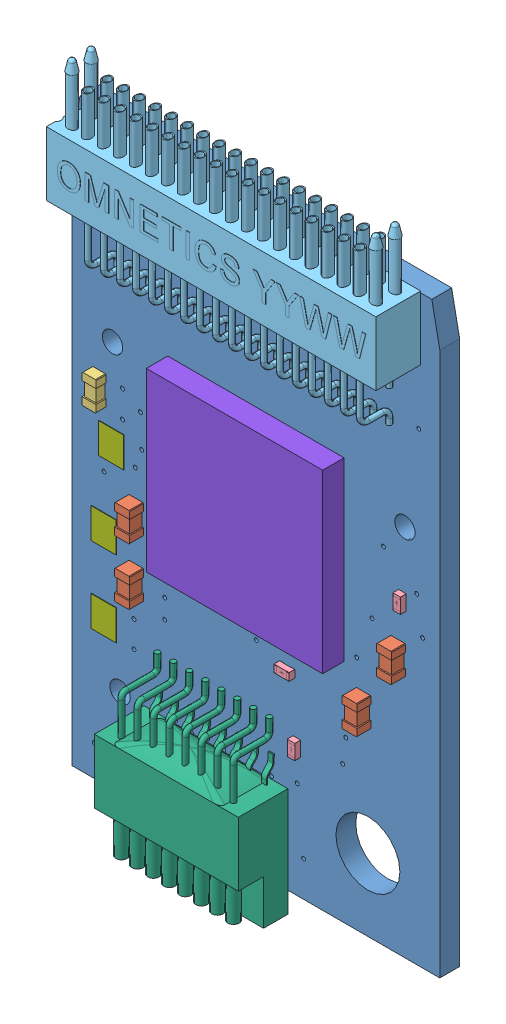
SolidWorks assembly RHS2116_32, configuration Default. Lengths in mm.
Overall size (14.61 26.43 3.68).
25 component instances, 8 part files, 50 mates.
Components (placement in the parent):
- RHD2116_32_PCB-1: RHD2116_32_PCB [Default] at origin size (14.61 23.18 0.79)
- 0402c_2320560-1: 0402c_2320560 [Default] at (12.9413 10.2362 0.7874) x (0 -1 0) z (0 0 1) size (1.15 0.6 0.55)
- 0402c_2320560-2: 0402c_2320560 [Default] at (2.54 7.62 0.7874) x (0 -1 0) z (0 0 1) size (1.15 0.6 0.55)
- 0402c_2320560-3: 0402c_2320560 [Default] at (2.54 9.8806 0.7874) x (0 -1 0) z (0 0 1) size (1.15 0.6 0.55)
- 0402c_2320560-4: 0402c_2320560 [Default] at (12.2174 12.3952 0) x (0 1 0) z (0 0 -1) size (1.15 0.6 0.55)
- 0402c_2320560-5: 0402c_2320560 [Default] at (4.0894 1.1938 0) x (1 0 0) z (0 0 -1) size (1.15 0.6 0.55)
- 0402c_2320560-6: 0402c_2320560 [Default] at (7.2898 1.1684 0) x (1 0 0) z (0 0 -1) size (1.15 0.6 0.55)
- 0402c_2320560-7: 0402c_2320560 [Default] at (11.5697 7.7597 0.7874) x (0 -1 0) z (0 0 1) size (1.15 0.6 0.55)
- 0402c_2320560-8: 0402c_2320560 [Default] at (2.8575 7.9375 0) x (0 -1 0) z (0 0 -1) size (1.15 0.6 0.55)
- 0402r_1430758-1: 0402r_1430758 [Default] at (1.0795 13.5634 0.7874) x (0 1 0) z (0 0 1) size (1.15 0.55 0.4)
- 0201r-1: 0201r [0201] at (8.9281 5.1181 0.9024) x (1 0 0) z (0 -1 0) size (0.3 0.23 0.6)
- 0201r-2: 0201r [0201] at (6.6294 2.3241 -0.115) x (0 1 0) z (-1 0 0) size (0.3 0.23 0.6)
- 0201r-3: 0201r [0201] at (8.5471 7.5819 0.9024) x (0 -1 0) z (-1 0 0) size (0.3 0.23 0.6)
- 0201r-4: 0201r [0201] at (4.953 2.6797 -0.115) x (0 -1 0) z (1 0 0) size (0.3 0.23 0.6)
- 0201r-5: 0201r [0201] at (13.1191 12.2428 0.9024) x (1 0 0) z (0 -1 0) size (0.3 0.23 0.6)
- A79025-001-1: A79025-001 [Default] at (6.0325 21.971 2.5654) size (13.15 7.44 2.12)
- A79633-001-1: A79633-001 [Default] at (5.715 3.4925 0.7874) x (1 0 0) z (0 -1 0) size (5.72 2.06 6.53)
- smd_pad_1_0_x_1_2-1: smd_pad_1_0_x_1_2 [Default] at (1.5748 11.811 0.8074) x (0 -1 0) z (1 0 0) size (1.2 0.02 1)
- smd_pad_1_0_x_1_2-2: smd_pad_1_0_x_1_2 [Default] at (1.27 8.7376 0.7874) x (0 1 0) z (1 0 0) size (1.2 0.02 1)
- smd_pad_1_0_x_1_2-3: smd_pad_1_0_x_1_2 [Default] at (1.27 5.715 0.7874) x (0 1 0) z (1 0 0) size (1.2 0.02 1)
- smd_pad_1_0_x_1_2-4: smd_pad_1_0_x_1_2 [Default] at (13.0175 7.3025 0) x (0 1 0) z (-1 0 0) size (1.2 0.02 1)
- smd_pad_1_0_x_1_2-5: smd_pad_1_0_x_1_2 [Default] at (13.0175 8.89 0) x (0 1 0) z (-1 0 0) size (1.2 0.02 1)
- smd_pad_1_0_x_1_2-6: smd_pad_1_0_x_1_2 [Default] at (13.0175 10.4775 0) x (0 1 0) z (-1 0 0) size (1.2 0.02 1)
- QFN_7x7mm-1: QFN_7x7mm [Default] at (3.8025 15.9841 0) x (1 0 0) z (0 1 0) size (7 0.85 7)
- QFN_7x7mm-2: QFN_7x7mm [Default] at (10.8025 15.9841 0.7874) x (-1 0 0) z (0 1 0) size (7 0.85 7)
Mates (geometry in assembly coordinates):
- Coincident1: coincident anti-aligned: plane of RHD2116_32-1 through (0 0 0.7874) normal (0 0 1); plane of QFN_7x7mm-2 through (10.8025 15.9841 0.7874) normal (0 0 -1)
- Parallel1: parallel aligned: plane of RHD2116_32-1 through (0 0 0.7874) normal (-1 0 0); plane of QFN_7x7mm-2 through (3.8025 15.9841 1.6374) normal (-1 0 0)
- Parallel2: parallel aligned: plane of RHD2116_32-1 through (14.605 21.59 0.7874) normal (1 0 0); plane of QFN_7x7mm-1 through (10.8025 15.9841 -0.85) normal (1 0 0)
- Coincident5: coincident anti-aligned: plane of RHD2116_32-1 through (0 0 0.7874) normal (0 0 1); plane of A79025-001-1 through (13.843 20.701 0.7874) normal (0 0 -1)
- Parallel3: parallel aligned: plane of RHD2116_32-1 through (14.605 21.59 0.7874) normal (1 0 0); plane of A79025-001-1 through (13.843 23.241 2.5654) normal (1 0 0)
- Coincident7: coincident anti-aligned: plane of RHD2116_32-1 through (0 0 0.7874) normal (0 0 1); plane of smd_pad_1_0_x_1_2-1 through (1.5748 11.811 0.7874) normal (0 0 -1)
- Coincident9: coincident anti-aligned: plane of RHD2116_32-1 through (0 0 0.7874) normal (0 0 1); plane of smd_pad_1_0_x_1_2-2 through (1.27 8.7376 0.7874) normal (0 0 -1)
- Coincident11: coincident anti-aligned: plane of RHD2116_32-1 through (0 0 0.7874) normal (0 0 1); plane of smd_pad_1_0_x_1_2-3 through (1.27 5.715 0.7874) normal (0 0 -1)
- Coincident13: coincident anti-aligned: plane of RHD2116_32-1 through (0 0 0.7874) normal (0 0 1); plane of 0402r_1430758-1 through (0.2545 13.5634 0.7874) normal (0 0 -1)
- Parallel7: parallel aligned: plane of RHD2116_32-1 through (0 0 0.7874) normal (-1 0 0); plane of 0402r_1430758-1 through (0.8045 14.1134 1.1874) normal (-1 0 0)
- Coincident14: coincident anti-aligned: plane of RHD2116_32-1 through (0 0 0.7874) normal (0 0 1); plane of 0402c_2320560-3 through (3.39 9.8806 0.7874) normal (0 0 -1)
- Parallel8: parallel aligned: plane of RHD2116_32-1 through (0 0 0.7874) normal (-1 0 0); plane of 0402c_2320560-3 through (2.24 10.4306 1.3374) normal (-1 0 0)
- Coincident15: coincident anti-aligned: plane of RHD2116_32-1 through (0 0 0.7874) normal (0 0 1); plane of 0402c_2320560-2 through (3.39 7.62 0.7874) normal (0 0 -1)
- Parallel9: parallel aligned: plane of RHD2116_32-1 through (0 0 0.7874) normal (-1 0 0); plane of 0402c_2320560-2 through (2.24 8.17 1.3374) normal (-1 0 0)
- Coincident16: coincident anti-aligned: plane of RHD2116_32-1 through (0 0 0.7874) normal (0 0 1); plane of 0402c_2320560-7 through (12.4197 7.7597 0.7874) normal (0 0 -1)
- Parallel10: parallel aligned: plane of RHD2116_32-1 through (14.605 21.59 0.7874) normal (1 0 0); plane of 0402c_2320560-7 through (11.8697 7.2097 1.3374) normal (1 0 0)
- Coincident18: coincident anti-aligned: plane of RHD2116_32-1 through (0 0 0.7874) normal (0 0 1); plane of 0402c_2320560-1 through (13.7913 10.2362 0.7874) normal (0 0 -1)
- Parallel11: parallel aligned: plane of RHD2116_32-1 through (14.605 21.59 0.7874) normal (1 0 0); plane of 0402c_2320560-1 through (13.2413 9.6862 1.3374) normal (1 0 0)
- Coincident19: coincident anti-aligned: plane of RHD2116_32-1 through (0 0 0.7874) normal (0 0 1); plane of 0201r-3 through (8.2471 7.4319 0.7874) normal (0 0 -1)
- Parallel12: parallel anti-aligned: plane of RHD2116_32-1 through (14.605 21.59 0.7874) normal (1 0 0); plane of 0201r-3 through (8.2471 7.4319 1.0174) normal (-1 0 0)
- Coincident21: coincident anti-aligned: plane of RHD2116_32-1 through (0 0 0.7874) normal (0 0 1); plane of 0201r-1 through (9.0781 4.8181 0.7874) normal (0 0 -1)
- Parallel13: parallel anti-aligned: plane of RHD2116_32-1 through (14.605 0 0.7874) normal (0 -1 0); plane of 0201r-1 through (9.0781 5.4181 1.0174) normal (0 1 0)
- Coincident23: coincident anti-aligned: plane of RHD2116_32-1 through (0 0 0.7874) normal (0 0 1); plane of 0201r-5 through (13.2691 11.9428 0.7874) normal (0 0 -1)
- Parallel14: parallel anti-aligned: plane of RHD2116_32-1 through (14.605 21.59 0.7874) normal (1 0 0); plane of 0201r-5 through (12.9691 11.9428 1.0174) normal (-1 0 0)
- Coincident25: coincident anti-aligned: plane of RHD2116_32-1 through (0 0 0.7874) normal (0 0 1); plane of A79633-001-1 through (5.715 3.4925 0.7874) normal (0 0 -1)
- Parallel15: parallel aligned: plane of RHD2116_32-1 through (14.605 0 0.7874) normal (0 -1 0); plane of A79633-001-1 through (5.715 -0.8255 0.7874) normal (0 -1 0)
- Parallel16: parallel anti-aligned: plane of RHD2116_32-1 through (0 0 0.7874) normal (-1 0 0); plane of smd_pad_1_0_x_1_2-1 through (2.0748 12.411 0.7874) normal (1 0 0)
- Parallel17: parallel anti-aligned: plane of RHD2116_32-1 through (0 0 0.7874) normal (-1 0 0); plane of smd_pad_1_0_x_1_2-2 through (1.77 8.1376 0.8074) normal (1 0 0)
- Parallel18: parallel anti-aligned: plane of RHD2116_32-1 through (0 0 0.7874) normal (-1 0 0); plane of smd_pad_1_0_x_1_2-3 through (1.77 5.115 0.8074) normal (1 0 0)
- Coincident30: coincident anti-aligned: plane of RHD2116_32-1 through (0 0 0) normal (0 0 -1); plane of QFN_7x7mm-1 through (3.8025 15.9841 0) normal (0 0 1)
- Coincident31: coincident anti-aligned: plane of RHD2116_32-1 through (0 0 0) normal (0 0 -1); plane of 0402c_2320560-4 through (13.0674 12.3952 0) normal (0 0 1)
- Parallel19: parallel aligned: plane of RHD2116_32-1 through (14.605 21.59 0.7874) normal (1 0 0); plane of 0402c_2320560-4 through (12.5174 12.9452 -0.55) normal (1 0 0)
- Coincident32: coincident anti-aligned: plane of RHD2116_32-1 through (0 0 0) normal (0 0 -1); plane of 0402c_2320560-8 through (2.0075 7.9375 0) normal (0 0 1)
- Parallel20: parallel aligned: plane of RHD2116_32-1 through (0 0 0.7874) normal (-1 0 0); plane of 0402c_2320560-8 through (2.5575 7.3875 -0.55) normal (-1 0 0)
- Coincident34: coincident anti-aligned: plane of RHD2116_32-1 through (0 0 0) normal (0 0 -1); plane of 0402c_2320560-6 through (7.2898 0.3184 0) normal (0 0 1)
- Parallel21: parallel aligned: plane of RHD2116_32-1 through (14.605 0 0.7874) normal (0 -1 0); plane of 0402c_2320560-6 through (7.8398 0.8684 -0.55) normal (0 -1 0)
- Coincident36: coincident anti-aligned: plane of RHD2116_32-1 through (0 0 0) normal (0 0 -1); plane of 0402c_2320560-5 through (4.0894 0.3438 0) normal (0 0 1)
- Parallel22: parallel aligned: plane of RHD2116_32-1 through (14.605 0 0.7874) normal (0 -1 0); plane of 0402c_2320560-5 through (4.6394 0.8938 -0.55) normal (0 -1 0)
- Coincident37: coincident anti-aligned: plane of RHD2116_32-1 through (0 0 0) normal (0 0 -1); plane of smd_pad_1_0_x_1_2-6 through (13.0175 10.4775 0) normal (0 0 1)
- Parallel23: parallel anti-aligned: plane of RHD2116_32-1 through (14.605 21.59 0.7874) normal (1 0 0); plane of smd_pad_1_0_x_1_2-6 through (12.5175 9.8775 -0.02) normal (-1 0 0)
- Coincident39: coincident anti-aligned: plane of RHD2116_32-1 through (0 0 0) normal (0 0 -1); plane of smd_pad_1_0_x_1_2-5 through (13.0175 8.89 0) normal (0 0 1)
- Parallel24: parallel anti-aligned: plane of RHD2116_32-1 through (14.605 21.59 0.7874) normal (1 0 0); plane of smd_pad_1_0_x_1_2-5 through (12.5175 8.29 -0.02) normal (-1 0 0)
- Coincident40: coincident anti-aligned: plane of RHD2116_32-1 through (0 0 0) normal (0 0 -1); plane of smd_pad_1_0_x_1_2-4 through (13.0175 7.3025 0) normal (0 0 1)
- Parallel25: parallel anti-aligned: plane of RHD2116_32-1 through (14.605 21.59 0.7874) normal (1 0 0); plane of smd_pad_1_0_x_1_2-4 through (12.5175 6.7025 -0.02) normal (-1 0 0)
- Coincident41: coincident anti-aligned: plane of RHD2116_32-1 through (0 0 0) normal (0 0 -1); plane of 0201r-2 through (6.3294 2.4741 0) normal (0 0 1)
- Parallel26: parallel anti-aligned: plane of RHD2116_32-1 through (14.605 21.59 0.7874) normal (1 0 0); plane of 0201r-2 through (6.3294 2.4741 -0.23) normal (-1 0 0)
- Coincident43: coincident anti-aligned: plane of RHD2116_32-1 through (0 0 0) normal (0 0 -1); plane of 0201r-4 through (5.253 2.5297 0) normal (0 0 1)
- Parallel27: parallel anti-aligned: plane of RHD2116_32-1 through (0 0 0.7874) normal (-1 0 0); plane of 0201r-4 through (5.253 2.5297 -0.23) normal (1 0 0)
- Distance1: distance = 0.762 mm: line of A79025-001-1 through (0.762 20.7271 0.7874) axis (0 1 0); line of RHD2116_32-1 through (0 21.59 0.7874) axis (0 -1 0)
- Distance3: distance = 0.0635 mm: line of A79025-001-1 through (0.762 23.241 0.7874) axis (1 0 0); line of RHD2116_32-1 through (14.2875 23.1775 0.7874) axis (-1 0 0)
